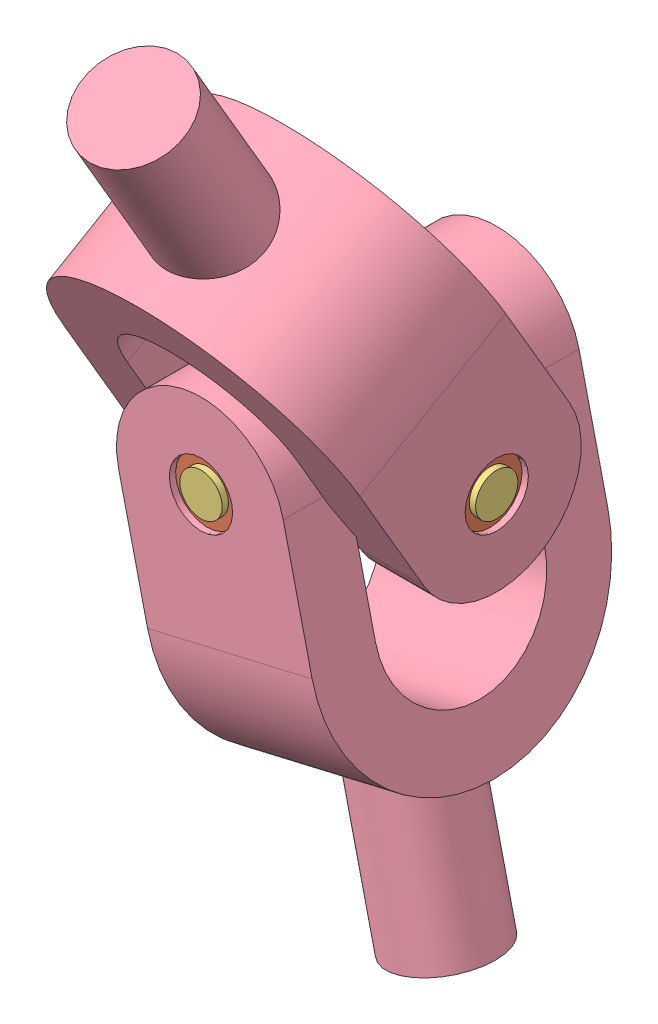
SolidWorks assembly Universal Joint 2003091, configuration Default. Lengths in mm.
Overall size (98.42 254.24 131.1).
11 component instances, 4 part files, 20 mates.
Components (placement in the parent):
- Swivel - 2003091-2: Swivel - 2003091 [Default] at origin size (54.61 25.4 54.61)
- Blushing 2003091-2: Blushing 2003091 [Default] at (0 0 -42.545) size (19.05 19.05 15.24)
- Blushing 2003091-3: Blushing 2003091 [Default] at (-42.545 0 0) x (0 0 -1) z (1 0 0) size (19.05 19.05 15.24)
- Blushing 2003091-4: Blushing 2003091 [Default] at (42.545 0 0) x (0 0 1) z (-1 0 0) size (19.05 19.05 15.24)
- Blushing 2003091-5: Blushing 2003091 [Default] at (0 0 42.545) x (-0.923728 -0.383049 0) z (0 0 -1) size (19.05 19.05 15.24)
- Pin 2003091-1: Pin 2003091 [Default] at (44.45 0 0) x (0 0 1) z (-1 0 0) size (12.7 12.7 34.29)
- Pin 2003091-2: Pin 2003091 [Default] at (0 0 44.45) x (-0.982483 0.186351 0) z (0 0 -1) size (12.7 12.7 34.29)
- Pin 2003091-3: Pin 2003091 [Default] at (0 0 -44.45) x (0.328176 -0.944616 0) z (0 0 1) size (12.7 12.7 34.29)
- Pin 2003091-4: Pin 2003091 [Default] at (-44.45 0 0) x (0 -0.31411 -0.949386) z (1 0 0) size (12.7 12.7 34.29)
- Yoke - 2003091-1: Yoke - 2003091 [Default] at (8.6847 -37.097 0) x (0 0 1) z (0.973674 0.227945 0) size (88.9 153.67 50.8)
- Yoke - 2003091-2: Yoke - 2003091 [Default] at (0 32.8948 19.2235) x (1 0 0) z (0 -0.504554 0.86338) size (88.9 153.67 50.8)
Mates (geometry in assembly coordinates):
- Coincident1: coincident anti-aligned: plane of Blushing 2003091-3 through (-27.305 0 0) normal (1 0 0); plane of Swivel - 2003091-2 through (-27.305 0 0) normal (-1 0 0)
- Coincident3: coincident anti-aligned: plane of Swivel - 2003091-2 through (0 0 27.305) normal (0 0 1); plane of Blushing 2003091-5 through (0 0 27.305) normal (0 0 -1)
- Coincident4: coincident anti-aligned: circle of Swivel - 2003091-2; circle of Blushing 2003091-5
- Coincident5: coincident anti-aligned: plane of Swivel - 2003091-2 through (27.305 0 0) normal (1 0 0); plane of Blushing 2003091-4 through (27.305 0 0) normal (-1 0 0)
- Coincident6: coincident anti-aligned: circle of Swivel - 2003091-2; circle of Blushing 2003091-4
- Coincident7: coincident anti-aligned: plane of Swivel - 2003091-2 through (0 0 -27.305) normal (0 0 -1); plane of Blushing 2003091-2 through (0 0 -27.305) normal (0 0 1)
- Coincident8: coincident aligned: circle of Swivel - 2003091-2; circle of Blushing 2003091-2
- Coincident9: coincident anti-aligned: cylinder of Blushing 2003091-4; cylinder of Pin 2003091-1 through (10.16 0 0) axis (1 0 0) radius 6.35
- Coincident10: coincident anti-aligned: circle of Blushing 2003091-5; cylinder of Pin 2003091-2 through (15.8616 -11.479 19.1621) axis (0 0 1) radius 6.35
- Coincident11: coincident anti-aligned: circle of Blushing 2003091-2; cylinder of Pin 2003091-3 through (0 0 -10.16) axis (0 0 -1) radius 6.35
- Coincident13: coincident aligned: circle of Swivel - 2003091-2; circle of Blushing 2003091-3
- Coincident14: coincident anti-aligned: circle of Blushing 2003091-3; cylinder of Pin 2003091-4 through (-23.276 28.0793 5.4499) axis (-1 0 0) radius 6.35
- Concentric4: concentric anti-aligned: cylinder of Blushing 2003091-3 through (-27.305 0 0) axis (-1 0 0) radius 9.525; cylinder of Yoke - 2003091-2 through (44.45 0 0) axis (1 0 0) radius 9.525
- Concentric6: concentric anti-aligned: cylinder of Blushing 2003091-2 through (0 0 -27.305) axis (0 0 -1) radius 9.525; cylinder of Yoke - 2003091-1 through (0 0 44.45) axis (0 0 1) radius 9.525
- Width1: width aligned: plane of Yoke - 2003091-1 through (33.416 -31.3072 -44.45) normal (0 0 -1); plane of Blushing 2003091-2 through (33.416 -31.3072 44.45) normal (0 0 1); plane of Yoke - 2003091-1 through (0 0 -42.545) normal (0 0 -1); plane of Blushing 2003091-5 through (0 0 42.545) normal (0 0 1)
- Width2: width aligned: plane of Yoke - 2003091-2 through (44.45 20.0791 41.1534) normal (1 0 0); plane of Blushing 2003091-4 through (-44.45 20.0791 41.1534) normal (-1 0 0); plane of Yoke - 2003091-2 through (42.545 0 0) normal (1 0 0); plane of Blushing 2003091-3 through (-42.545 0 0) normal (-1 0 0)
- Coincident24: coincident aligned: plane of Pin 2003091-1 through (44.45 0 0) normal (1 0 0); plane of Yoke - 2003091-2 through (44.45 20.0791 41.1534) normal (1 0 0)
- Coincident25: coincident aligned: plane of Pin 2003091-3 through (0 0 -44.45) normal (0 0 -1); plane of Yoke - 2003091-1 through (33.416 -31.3072 -44.45) normal (0 0 -1)
- Coincident26: coincident aligned: plane of Pin 2003091-4 through (-44.45 0 0) normal (-1 0 0); plane of Yoke - 2003091-2 through (-44.45 20.0791 41.1534) normal (-1 0 0)
- Coincident27: coincident aligned: plane of Pin 2003091-2 through (0 0 44.45) normal (0 0 1); plane of Yoke - 2003091-1 through (33.416 -31.3072 44.45) normal (0 0 1)
